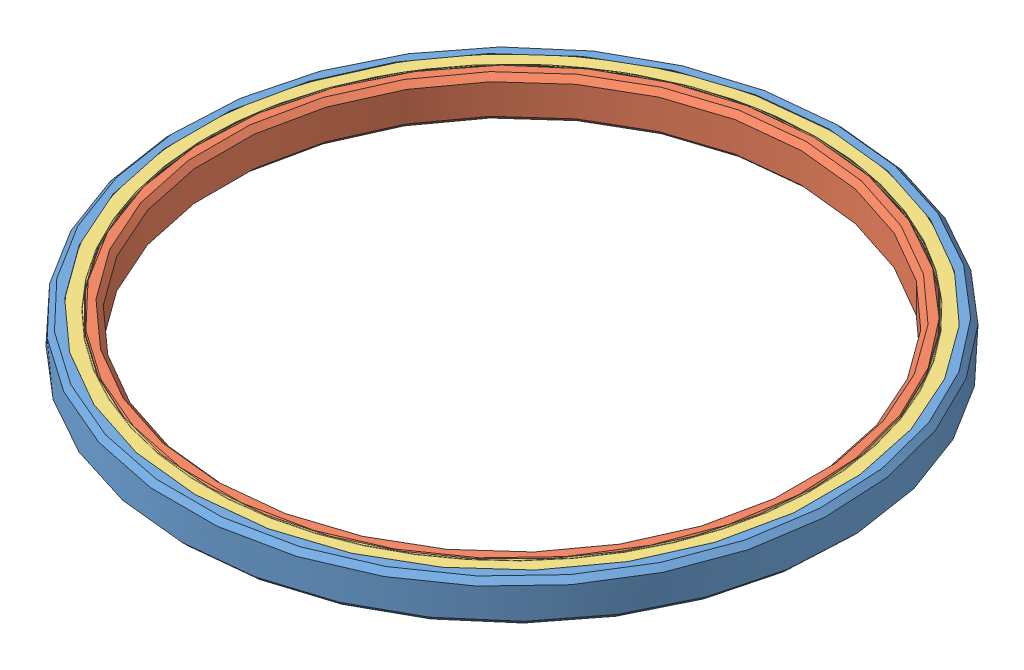
SolidWorks assembly SW3dPS-JB - Four-Point Contact, configuration JB045XP0. Lengths in mm.
Overall size (130.18 7.94 130.18).
54 component instances, 5 part files, 12 mates.
Components (placement in the parent):
- SW3dPS-JB - Four-Point Contact_JB OUTER CATALOG-1: SW3dPS-JB - Four-Point Contact_JB OUTER CATALOG [JB045002] at origin size (130.18 7.94 130.18)
- SW3dPS-JB - Four-Point Contact_JB INNER CATALOG-1: SW3dPS-JB - Four-Point Contact_JB INNER CATALOG [JB045003] at origin size (120.17 7.94 120.17)
- SW3dPS-JB - Four-Point Contact_JB SEPARATOR SAMPLE-1: SW3dPS-JB - Four-Point Contact_JB SEPARATOR SAMPLE [JB045] at origin size (126.21 5.54 126.21)
  - SW3dPS-JB - Four-Point Contact_JB SEPARATOR SAMPLE-1: SW3dPS-JB - Four-Point Contact_JB SEPARATOR SAMPLE [JB045] at origin size (123.23 5.08 123.23)
  - SW3dPS-JB - Four-Point Contact_JB SIZE CATALOG BALL-1: SW3dPS-JB - Four-Point Contact_JB SIZE CATALOG BALL [JB045] at origin size (3.97 3.97 3.97)
  - SW3dPS-JB - Four-Point Contact_JB SIZE CATALOG BALL-2: SW3dPS-JB - Four-Point Contact_JB SIZE CATALOG BALL [JB045] x (0.991445 0 -0.130526) z (0.130526 0 0.991445) size (3.97 3.97 3.97)
  - SW3dPS-JB - Four-Point Contact_JB SIZE CATALOG BALL-3: SW3dPS-JB - Four-Point Contact_JB SIZE CATALOG BALL [JB045] x (0.965926 0 -0.258819) z (0.258819 0 0.965926) size (3.97 3.97 3.97)
  - SW3dPS-JB - Four-Point Contact_JB SIZE CATALOG BALL-4: SW3dPS-JB - Four-Point Contact_JB SIZE CATALOG BALL [JB045] x (0.92388 0 -0.382683) z (0.382683 0 0.92388) size (3.97 3.97 3.97)
  - SW3dPS-JB - Four-Point Contact_JB SIZE CATALOG BALL-5: SW3dPS-JB - Four-Point Contact_JB SIZE CATALOG BALL [JB045] x (0.866025 0 -0.5) z (0.5 0 0.866025) size (3.97 3.97 3.97)
  - SW3dPS-JB - Four-Point Contact_JB SIZE CATALOG BALL-6: SW3dPS-JB - Four-Point Contact_JB SIZE CATALOG BALL [JB045] x (0.793353 0 -0.608761) z (0.608761 0 0.793353) size (3.97 3.97 3.97)
  - SW3dPS-JB - Four-Point Contact_JB SIZE CATALOG BALL-7: SW3dPS-JB - Four-Point Contact_JB SIZE CATALOG BALL [JB045] x (0.707107 0 -0.707107) z (0.707107 0 0.707107) size (3.97 3.97 3.97)
  - SW3dPS-JB - Four-Point Contact_JB SIZE CATALOG BALL-8: SW3dPS-JB - Four-Point Contact_JB SIZE CATALOG BALL [JB045] x (0.608761 0 -0.793353) z (0.793353 0 0.608761) size (3.97 3.97 3.97)
  - SW3dPS-JB - Four-Point Contact_JB SIZE CATALOG BALL-9: SW3dPS-JB - Four-Point Contact_JB SIZE CATALOG BALL [JB045] x (0.5 0 -0.866025) z (0.866025 0 0.5) size (3.97 3.97 3.97)
  - SW3dPS-JB - Four-Point Contact_JB SIZE CATALOG BALL-10: SW3dPS-JB - Four-Point Contact_JB SIZE CATALOG BALL [JB045] x (0.382683 0 -0.92388) z (0.92388 0 0.382683) size (3.97 3.97 3.97)
  - SW3dPS-JB - Four-Point Contact_JB SIZE CATALOG BALL-11: SW3dPS-JB - Four-Point Contact_JB SIZE CATALOG BALL [JB045] x (0.258819 0 -0.965926) z (0.965926 0 0.258819) size (3.97 3.97 3.97)
  - SW3dPS-JB - Four-Point Contact_JB SIZE CATALOG BALL-12: SW3dPS-JB - Four-Point Contact_JB SIZE CATALOG BALL [JB045] x (0.130526 0 -0.991445) z (0.991445 0 0.130526) size (3.97 3.97 3.97)
  - SW3dPS-JB - Four-Point Contact_JB SIZE CATALOG BALL-13: SW3dPS-JB - Four-Point Contact_JB SIZE CATALOG BALL [JB045] x (0 0 -1) z (1 0 0) size (3.97 3.97 3.97)
  - SW3dPS-JB - Four-Point Contact_JB SIZE CATALOG BALL-14: SW3dPS-JB - Four-Point Contact_JB SIZE CATALOG BALL [JB045] x (-0.130526 0 -0.991445) z (0.991445 0 -0.130526) size (3.97 3.97 3.97)
  - SW3dPS-JB - Four-Point Contact_JB SIZE CATALOG BALL-15: SW3dPS-JB - Four-Point Contact_JB SIZE CATALOG BALL [JB045] x (-0.258819 0 -0.965926) z (0.965926 0 -0.258819) size (3.97 3.97 3.97)
  - SW3dPS-JB - Four-Point Contact_JB SIZE CATALOG BALL-16: SW3dPS-JB - Four-Point Contact_JB SIZE CATALOG BALL [JB045] x (-0.382683 0 -0.92388) z (0.92388 0 -0.382683) size (3.97 3.97 3.97)
  - SW3dPS-JB - Four-Point Contact_JB SIZE CATALOG BALL-17: SW3dPS-JB - Four-Point Contact_JB SIZE CATALOG BALL [JB045] x (-0.5 0 -0.866025) z (0.866025 0 -0.5) size (3.97 3.97 3.97)
  - SW3dPS-JB - Four-Point Contact_JB SIZE CATALOG BALL-18: SW3dPS-JB - Four-Point Contact_JB SIZE CATALOG BALL [JB045] x (-0.608761 0 -0.793353) z (0.793353 0 -0.608761) size (3.97 3.97 3.97)
  - SW3dPS-JB - Four-Point Contact_JB SIZE CATALOG BALL-19: SW3dPS-JB - Four-Point Contact_JB SIZE CATALOG BALL [JB045] x (-0.707107 0 -0.707107) z (0.707107 0 -0.707107) size (3.97 3.97 3.97)
  - SW3dPS-JB - Four-Point Contact_JB SIZE CATALOG BALL-20: SW3dPS-JB - Four-Point Contact_JB SIZE CATALOG BALL [JB045] x (-0.793353 0 -0.608761) z (0.608761 0 -0.793353) size (3.97 3.97 3.97)
  - SW3dPS-JB - Four-Point Contact_JB SIZE CATALOG BALL-21: SW3dPS-JB - Four-Point Contact_JB SIZE CATALOG BALL [JB045] x (-0.866025 0 -0.5) z (0.5 0 -0.866025) size (3.97 3.97 3.97)
  - SW3dPS-JB - Four-Point Contact_JB SIZE CATALOG BALL-22: SW3dPS-JB - Four-Point Contact_JB SIZE CATALOG BALL [JB045] x (-0.92388 0 -0.382683) z (0.382683 0 -0.92388) size (3.97 3.97 3.97)
  - SW3dPS-JB - Four-Point Contact_JB SIZE CATALOG BALL-23: SW3dPS-JB - Four-Point Contact_JB SIZE CATALOG BALL [JB045] x (-0.965926 0 -0.258819) z (0.258819 0 -0.965926) size (3.97 3.97 3.97)
  - SW3dPS-JB - Four-Point Contact_JB SIZE CATALOG BALL-24: SW3dPS-JB - Four-Point Contact_JB SIZE CATALOG BALL [JB045] x (-0.991445 0 -0.130526) z (0.130526 0 -0.991445) size (3.97 3.97 3.97)
  - SW3dPS-JB - Four-Point Contact_JB SIZE CATALOG BALL-25: SW3dPS-JB - Four-Point Contact_JB SIZE CATALOG BALL [JB045] x (-1 0 0) z (0 0 -1) size (3.97 3.97 3.97)
  - SW3dPS-JB - Four-Point Contact_JB SIZE CATALOG BALL-26: SW3dPS-JB - Four-Point Contact_JB SIZE CATALOG BALL [JB045] x (-0.991445 0 0.130526) z (-0.130526 0 -0.991445) size (3.97 3.97 3.97)
  - SW3dPS-JB - Four-Point Contact_JB SIZE CATALOG BALL-27: SW3dPS-JB - Four-Point Contact_JB SIZE CATALOG BALL [JB045] x (-0.965926 0 0.258819) z (-0.258819 0 -0.965926) size (3.97 3.97 3.97)
  - SW3dPS-JB - Four-Point Contact_JB SIZE CATALOG BALL-28: SW3dPS-JB - Four-Point Contact_JB SIZE CATALOG BALL [JB045] x (-0.92388 0 0.382683) z (-0.382683 0 -0.92388) size (3.97 3.97 3.97)
  - SW3dPS-JB - Four-Point Contact_JB SIZE CATALOG BALL-29: SW3dPS-JB - Four-Point Contact_JB SIZE CATALOG BALL [JB045] x (-0.866025 0 0.5) z (-0.5 0 -0.866025) size (3.97 3.97 3.97)
  - SW3dPS-JB - Four-Point Contact_JB SIZE CATALOG BALL-30: SW3dPS-JB - Four-Point Contact_JB SIZE CATALOG BALL [JB045] x (-0.793353 0 0.608761) z (-0.608761 0 -0.793353) size (3.97 3.97 3.97)
  - SW3dPS-JB - Four-Point Contact_JB SIZE CATALOG BALL-31: SW3dPS-JB - Four-Point Contact_JB SIZE CATALOG BALL [JB045] x (-0.707107 0 0.707107) z (-0.707107 0 -0.707107) size (3.97 3.97 3.97)
  - SW3dPS-JB - Four-Point Contact_JB SIZE CATALOG BALL-32: SW3dPS-JB - Four-Point Contact_JB SIZE CATALOG BALL [JB045] x (-0.608761 0 0.793353) z (-0.793353 0 -0.608761) size (3.97 3.97 3.97)
  - SW3dPS-JB - Four-Point Contact_JB SIZE CATALOG BALL-33: SW3dPS-JB - Four-Point Contact_JB SIZE CATALOG BALL [JB045] x (-0.5 0 0.866025) z (-0.866025 0 -0.5) size (3.97 3.97 3.97)
  - SW3dPS-JB - Four-Point Contact_JB SIZE CATALOG BALL-34: SW3dPS-JB - Four-Point Contact_JB SIZE CATALOG BALL [JB045] x (-0.382683 0 0.92388) z (-0.92388 0 -0.382683) size (3.97 3.97 3.97)
  - SW3dPS-JB - Four-Point Contact_JB SIZE CATALOG BALL-35: SW3dPS-JB - Four-Point Contact_JB SIZE CATALOG BALL [JB045] x (-0.258819 0 0.965926) z (-0.965926 0 -0.258819) size (3.97 3.97 3.97)
  - SW3dPS-JB - Four-Point Contact_JB SIZE CATALOG BALL-36: SW3dPS-JB - Four-Point Contact_JB SIZE CATALOG BALL [JB045] x (-0.130526 0 0.991445) z (-0.991445 0 -0.130526) size (3.97 3.97 3.97)
  - SW3dPS-JB - Four-Point Contact_JB SIZE CATALOG BALL-37: SW3dPS-JB - Four-Point Contact_JB SIZE CATALOG BALL [JB045] x (0 0 1) z (-1 0 0) size (3.97 3.97 3.97)
  - SW3dPS-JB - Four-Point Contact_JB SIZE CATALOG BALL-38: SW3dPS-JB - Four-Point Contact_JB SIZE CATALOG BALL [JB045] x (0.130526 0 0.991445) z (-0.991445 0 0.130526) size (3.97 3.97 3.97)
  - SW3dPS-JB - Four-Point Contact_JB SIZE CATALOG BALL-39: SW3dPS-JB - Four-Point Contact_JB SIZE CATALOG BALL [JB045] x (0.258819 0 0.965926) z (-0.965926 0 0.258819) size (3.97 3.97 3.97)
  - SW3dPS-JB - Four-Point Contact_JB SIZE CATALOG BALL-40: SW3dPS-JB - Four-Point Contact_JB SIZE CATALOG BALL [JB045] x (0.382683 0 0.92388) z (-0.92388 0 0.382683) size (3.97 3.97 3.97)
  - SW3dPS-JB - Four-Point Contact_JB SIZE CATALOG BALL-41: SW3dPS-JB - Four-Point Contact_JB SIZE CATALOG BALL [JB045] x (0.5 0 0.866025) z (-0.866025 0 0.5) size (3.97 3.97 3.97)
  - SW3dPS-JB - Four-Point Contact_JB SIZE CATALOG BALL-42: SW3dPS-JB - Four-Point Contact_JB SIZE CATALOG BALL [JB045] x (0.608761 0 0.793353) z (-0.793353 0 0.608761) size (3.97 3.97 3.97)
  - SW3dPS-JB - Four-Point Contact_JB SIZE CATALOG BALL-43: SW3dPS-JB - Four-Point Contact_JB SIZE CATALOG BALL [JB045] x (0.707107 0 0.707107) z (-0.707107 0 0.707107) size (3.97 3.97 3.97)
  - SW3dPS-JB - Four-Point Contact_JB SIZE CATALOG BALL-44: SW3dPS-JB - Four-Point Contact_JB SIZE CATALOG BALL [JB045] x (0.793353 0 0.608761) z (-0.608761 0 0.793353) size (3.97 3.97 3.97)
  - SW3dPS-JB - Four-Point Contact_JB SIZE CATALOG BALL-45: SW3dPS-JB - Four-Point Contact_JB SIZE CATALOG BALL [JB045] x (0.866025 0 0.5) z (-0.5 0 0.866025) size (3.97 3.97 3.97)
  - SW3dPS-JB - Four-Point Contact_JB SIZE CATALOG BALL-46: SW3dPS-JB - Four-Point Contact_JB SIZE CATALOG BALL [JB045] x (0.92388 0 0.382683) z (-0.382683 0 0.92388) size (3.97 3.97 3.97)
  - SW3dPS-JB - Four-Point Contact_JB SIZE CATALOG BALL-47: SW3dPS-JB - Four-Point Contact_JB SIZE CATALOG BALL [JB045] x (0.965926 0 0.258819) z (-0.258819 0 0.965926) size (3.97 3.97 3.97)
  - SW3dPS-JB - Four-Point Contact_JB SIZE CATALOG BALL-48: SW3dPS-JB - Four-Point Contact_JB SIZE CATALOG BALL [JB045] x (0.991445 0 0.130526) z (-0.130526 0 0.991445) size (3.97 3.97 3.97)
- SW3dPS-JB - Four-Point Contact_JB SEAL-1: SW3dPS-JB - Four-Point Contact_JB SEAL [JB045] at (0 3.8811 0) size (125.35 0.75 125.35)
- SW3dPS-JB - Four-Point Contact_JB SEAL-2: SW3dPS-JB - Four-Point Contact_JB SEAL [JB045] at (0 -2.5324 0) x (1 0 0) z (0 0 -1) size (125.35 0.75 125.35)
Mates (geometry in assembly coordinates):
- Concentric2: concentric aligned: cylinder of ?; cylinder of SW3dPS-JB - Four-Point Contact_JB INNER CATALOG-1
- Coincident1: coincident: point of ?; point of SW3dPS-JB - Four-Point Contact_JB INNER CATALOG-1
- Coincident2: coincident: point of SW3dPS-JB - Four-Point Contact_JB INNER CATALOG-1; point of assembly
- Concentric3: concentric aligned: cylinder of SW3dPS-JB - Four-Point Contact_JB OUTER CATALOG-1; cylinder of SW3dPS-JB - Four-Point Contact_JB INNER CATALOG-1
- Coincident3: coincident aligned: plane of SW3dPS-JB - Four-Point Contact_JB INNER CATALOG-1; plane of assembly
- Coincident4: coincident aligned: plane of ?; plane of assembly
- Concentric4: concentric aligned: cylinder of SW3dPS-JB - Four-Point Contact_JB OUTER CATALOG-1; cylinder of SW3dPS-JB - Four-Point Contact_JB SEAL-1
- Coincident5: coincident aligned: plane of SW3dPS-JB - Four-Point Contact_JB SEAL-1; plane of assembly
- Concentric5: concentric anti-aligned: cylinder of SW3dPS-JB - Four-Point Contact_JB OUTER CATALOG-1; cylinder of SW3dPS-JB - Four-Point Contact_JB SEAL-2
- Coincident6: coincident anti-aligned: plane of SW3dPS-JB - Four-Point Contact_JB SEAL-2; plane of assembly
- Coincident7: coincident anti-aligned: plane of SW3dPS-JB - Four-Point Contact_JB OUTER CATALOG-1; plane of SW3dPS-JB - Four-Point Contact_JB SEAL-1
- Coincident8: coincident anti-aligned: plane of SW3dPS-JB - Four-Point Contact_JB OUTER CATALOG-1; plane of SW3dPS-JB - Four-Point Contact_JB SEAL-2
